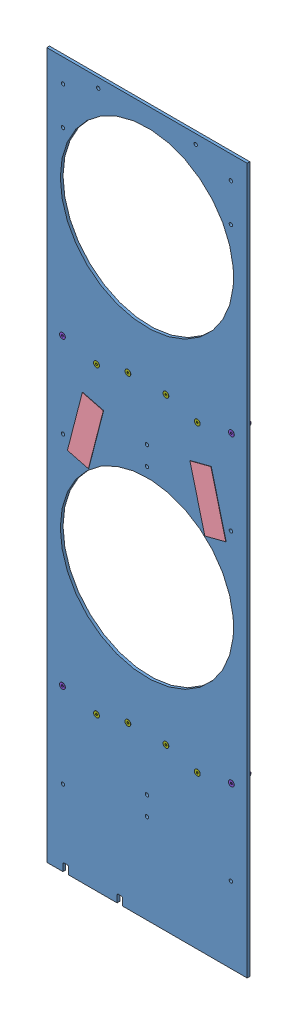
SolidWorks assembly GE-19128, configuration Default. Lengths in mm.
Overall size (469.9 1654.81 45.24).
39 component instances, 8 part files, 83 mates.
Components (placement in the parent):
- GE-19124-1: GE-19124 [Default] at origin size (469.9 1654.81 6.35)
- GE-19029-1: GE-19029 [Default] at (-12.7 406.807 0) x (0 0 -1) z (-0.965926 -0.258819 0) size (38.1 38.1 152.4)
- GE-19029-2: GE-19029 [Default] at (-12.7 1118.007 0) x (0 0 -1) z (-0.965926 -0.258819 0) size (38.1 38.1 152.4)
- GE-19029-3: GE-19029 [Default] at (159.9071 367.363 0) x (0 0 -1) z (-0.965926 0.258819 0) size (38.1 38.1 152.4)
- GE-19029-4: GE-19029 [Default] at (159.9071 1078.563 0) x (0 0 -1) z (-0.965926 0.258819 0) size (38.1 38.1 152.4)
- spacer_.257_1_.5-1: spacer_.257_1_.5 [Default] at (198.12 1088.0459 -25.4) x (-0.923728 -0.383049 0) z (-0.383049 0.923728 0) size (12.7 25.4 12.7)
- spacer_.257_1_.5-2: spacer_.257_1_.5 [Default] at (-198.12 1088.0459 -25.4) x (-0.923728 -0.383049 0) z (-0.383049 0.923728 0) size (12.7 25.4 12.7)
- spacer_.257_1_.5-3: spacer_.257_1_.5 [Default] at (-198.12 376.8459 -25.4) x (-0.923728 -0.383049 0) z (-0.383049 0.923728 0) size (12.7 25.4 12.7)
- spacer_.257_1_.5-4: spacer_.257_1_.5 [Default] at (198.12 376.8459 -25.4) x (-0.923728 -0.383049 0) z (-0.383049 0.923728 0) size (12.7 25.4 12.7)
- VisionTape-1: VisionTape [Default] at (185.7119 861.6861 7.1437) x (-0.968246 -0.25 0) z (0 0 -1) size (50.8 139.7 0.79)
- VisionTape-2: VisionTape [Default] at (-136.525 848.9861 7.1437) x (-0.968246 0.25 0) z (0 0 -1) size (50.8 139.7 0.79)
- nylock_.25_20-1: nylock_.25_20 [Default] at (-198.12 376.8459 -25.4) x (1 0 0) z (0 1 0) size (11.11 7.94 12.83)
- nylock_.25_20-2: nylock_.25_20 [Default] at (-118.1748 358.8231 -3.175) x (0.987351 0.158553 0) z (-0.158553 0.987351 0) size (11.11 7.94 12.83)
- nylock_.25_20-4: nylock_.25_20 [Default] at (-44.5713 378.5452 -3.175) x (0.959125 0.282984 0) z (-0.282984 0.959125 0) size (11.11 7.94 12.83)
- nylock_.25_20-6: nylock_.25_20 [Default] at (44.5713 378.5452 -3.175) x (0.928571 0.371154 0) z (-0.371154 0.928571 0) size (11.11 7.94 12.83)
- nylock_.25_20-8: nylock_.25_20 [Default] at (118.1748 358.8231 -3.175) x (0.906989 0.421154 0) z (-0.421154 0.906989 0) size (11.11 7.94 12.83)
- nylock_.25_20-10: nylock_.25_20 [Default] at (198.12 376.8459 -25.4) x (0.902849 0.429957 0) z (-0.429957 0.902849 0) size (11.11 7.94 12.83)
- nylock_.25_20-12: nylock_.25_20 [Default] at (-198.12 1088.0459 -25.4) x (0.919615 0.39282 0) z (-0.39282 0.919615 0) size (11.11 7.94 12.83)
- nylock_.25_20-14: nylock_.25_20 [Default] at (-118.1748 1070.0231 -3.175) x (0.952324 0.305088 0) z (-0.305088 0.952324 0) size (11.11 7.94 12.83)
- nylock_.25_20-16: nylock_.25_20 [Default] at (-44.5713 1089.7452 -3.175) x (0.985697 0.168526 0) z (-0.168526 0.985697 0) size (11.11 7.94 12.83)
- nylock_.25_20-18: nylock_.25_20 [Default] at (44.5713 1089.7452 -3.175) x (1 0 0) z (0 1 0) size (11.11 7.94 12.83)
- nylock_.25_20-20: nylock_.25_20 [Default] at (118.1748 1070.0231 -3.175) x (0.985697 -0.168526 0) z (0.168526 0.985697 0) size (11.11 7.94 12.83)
- nylock_.25_20-22: nylock_.25_20 [Default] at (198.12 1088.0459 -25.4) x (0.952324 -0.305088 0) z (0.305088 0.952324 0) size (11.11 7.94 12.83)
- Hook_1_6-1: Hook_1_6 [Default] at (12.7 1118.007 -6.35) x (0.965926 -0.258819 0) z (0 0 1) size (152.4 1.59 25.4)
- Hook_1_6-2: Hook_1_6 [Default] at (-159.9071 1078.563 -6.35) x (0.965926 0.258819 0) z (0 0 1) size (152.4 1.59 25.4)
- Hook_1_6-3: Hook_1_6 [Default] at (12.7 406.807 -6.35) x (0.965926 -0.258819 0) z (0 0 1) size (152.4 1.59 25.4)
- Hook_1_6-4: Hook_1_6 [Default] at (-159.9071 367.363 -6.35) x (0.965926 0.258819 0) z (0 0 1) size (152.4 1.59 25.4)
- flat_hex_.25_20_1-1: flat_hex_.25_20_1 [91253A542] at (-118.1748 1070.0231 6.5545) size (13.49 13.49 25.61)
- flat_hex_.25_20_1-9: flat_hex_.25_20_1 [91253A542] at (-44.5713 1089.7452 6.5545) x (0.987351 0.158553 0) z (0 0 1) size (13.49 13.49 25.61)
- flat_hex_.25_20_1-11: flat_hex_.25_20_1 [91253A542] at (44.5713 1089.7452 6.5545) x (0.959125 0.282984 0) z (0 0 1) size (13.49 13.49 25.61)
- flat_hex_.25_20_1-13: flat_hex_.25_20_1 [91253A542] at (118.1748 1070.0231 6.5545) x (0.928571 0.371154 0) z (0 0 1) size (13.49 13.49 25.61)
- flat_hex_.25_20_1-15: flat_hex_.25_20_1 [91253A542] at (-118.1748 358.8231 6.5545) x (0.906989 0.421154 0) z (0 0 1) size (13.49 13.49 25.61)
- flat_hex_.25_20_1-17: flat_hex_.25_20_1 [91253A542] at (-44.5713 378.5452 6.5545) x (0.902849 0.429957 0) z (0 0 1) size (13.49 13.49 25.61)
- flat_hex_.25_20_1-19: flat_hex_.25_20_1 [91253A542] at (44.5713 378.5452 6.5545) x (0.919615 0.39282 0) z (0 0 1) size (13.49 13.49 25.61)
- flat_hex_.25_20_1-21: flat_hex_.25_20_1 [91253A542] at (118.1748 358.8231 6.5545) x (0.952324 0.305088 0) z (0 0 1) size (13.49 13.49 25.61)
- flat_hex_.25_20_1.75-1: flat_hex_.25_20_1.75 [91253A548] at (-198.12 376.8459 6.5545) size (13.49 13.49 44.66)
- flat_hex_.25_20_1.75-2: flat_hex_.25_20_1.75 [91253A548] at (198.12 376.8459 6.5545) x (0.987351 0.158553 0) z (0 0 1) size (13.49 13.49 44.66)
- flat_hex_.25_20_1.75-4: flat_hex_.25_20_1.75 [91253A548] at (-198.12 1088.0459 6.5545) x (0.959125 0.282984 0) z (0 0 1) size (13.49 13.49 44.66)
- flat_hex_.25_20_1.75-6: flat_hex_.25_20_1.75 [91253A548] at (198.12 1088.0459 6.5545) x (0.928571 0.371154 0) z (0 0 1) size (13.49 13.49 44.66)
Mates (geometry in assembly coordinates):
- Coincident1: coincident: circle of GE-19124-1; unknown of GE-19029-1
- Coincident9: coincident: plane of GE-19124-1 through (0 0 0) normal (0 0 -1); plane of spacer_.257_1_.5-4 through (198.12 376.8459 0) normal (0 0 1)
- Coincident10: coincident: plane of GE-19124-1 through (0 0 0) normal (0 0 -1); plane of spacer_.257_1_.5-3 through (-198.12 376.8459 0) normal (0 0 1)
- Coincident11: coincident: plane of GE-19124-1 through (0 0 0) normal (0 0 -1); plane of spacer_.257_1_.5-2 through (-198.12 1088.0459 0) normal (0 0 1)
- Coincident12: coincident: plane of GE-19124-1 through (0 0 0) normal (0 0 -1); plane of spacer_.257_1_.5-1 through (198.12 1088.0459 0) normal (0 0 1)
- Concentric5: concentric: cylinder of GE-19124-1 through (-118.1748 358.8231 6.35) axis (0 0 1) radius 3.3782; cylinder of GE-19029-1 through (-118.1748 358.8231 0) axis (0 0 1) radius 3.3782
- Coincident13: coincident: circle of GE-19124-1; circle of GE-19029-3
- Concentric6: concentric: cylinder of GE-19124-1 through (118.1748 358.8231 6.35) axis (0 0 1) radius 3.3782; cylinder of GE-19029-3 through (118.1748 358.8231 0) axis (0 0 1) radius 3.3782
- Coincident14: coincident: circle of GE-19124-1; circle of GE-19029-4
- Concentric7: concentric: cylinder of GE-19124-1 through (118.1748 1070.0231 6.35) axis (0 0 1) radius 3.3782; cylinder of GE-19029-4 through (118.1748 1070.0231 0) axis (0 0 1) radius 3.3782
- Coincident15: coincident: circle of GE-19124-1; circle of GE-19029-2
- Concentric8: concentric: cylinder of GE-19124-1 through (-118.1748 1070.0231 6.35) axis (0 0 1) radius 3.3782; cylinder of GE-19029-2 through (-118.1748 1070.0231 0) axis (0 0 1) radius 3.3782
- Concentric9: concentric: circle of GE-19124-1; circle of spacer_.257_1_.5-1
- Concentric10: concentric: circle of GE-19124-1; circle of spacer_.257_1_.5-2
- Concentric11: concentric: circle of GE-19124-1; circle of spacer_.257_1_.5-4
- Concentric12: concentric: circle of GE-19124-1; circle of spacer_.257_1_.5-3
- Coincident16: coincident: plane of GE-19124-1 through (0 0 6.35) normal (0 0 1); plane of ? through (-132.5429 873.8959 6.35) normal (0 0 -1)
- Coincident17: coincident: plane of GE-19124-1 through (0 0 6.35) normal (0 0 1); plane of ? through (188.1614 861.6861 6.35) normal (0 0 -1)
- Distance1: distance = 203.2 mm: point of assembly; point of assembly; point of VisionTape-2; point of VisionTape-1
- Symmetric2: symmetric: plane of ? through (138.9745 848.9861 6.35) normal (-0.968246 -0.25 0); plane of ? through (-132.5429 873.8959 6.35) normal (0.968246 -0.25 0)
- Coincident42: coincident: plane of assembly; plane of assembly; plane of spacer_.257_1_.5-3 through (-198.12 376.8459 -25.4) normal (0 0 -1); plane of nylock_.25_20-1 through (-198.12 376.8459 -25.4) normal (0 0 1)
- Coincident43: coincident: plane of assembly; plane of assembly; plane of GE-19029-1 through (-150.0461 330.5612 -3.175) normal (0 0 -1); plane of nylock_.25_20-2 through (-118.1748 358.8231 -3.175) normal (0 0 1)
- Coincident44: coincident: plane of assembly; plane of assembly; plane of GE-19029-1 through (-150.0461 330.5612 -3.175) normal (0 0 -1); plane of nylock_.25_20-4 through (-44.5713 378.5452 -3.175) normal (0 0 1)
- Coincident45: coincident: plane of assembly; plane of assembly; plane of GE-19029-3 through (2.839 370.0053 -3.175) normal (0 0 -1); plane of nylock_.25_20-6 through (44.5713 378.5452 -3.175) normal (0 0 1)
- Coincident46: coincident: plane of assembly; plane of assembly; plane of GE-19029-3 through (2.839 370.0053 -3.175) normal (0 0 -1); plane of nylock_.25_20-8 through (118.1748 358.8231 -3.175) normal (0 0 1)
- Coincident47: coincident: plane of assembly; plane of assembly; plane of spacer_.257_1_.5-4 through (198.12 376.8459 -25.4) normal (0 0 -1); plane of nylock_.25_20-10 through (198.12 376.8459 -25.4) normal (0 0 1)
- Coincident48: coincident: plane of assembly; plane of assembly; plane of spacer_.257_1_.5-2 through (-198.12 1088.0459 -25.4) normal (0 0 -1); plane of nylock_.25_20-12 through (-198.12 1088.0459 -25.4) normal (0 0 1)
- Coincident49: coincident: plane of assembly; plane of assembly; plane of GE-19029-2 through (-150.0461 1041.7612 -3.175) normal (0 0 -1); plane of nylock_.25_20-14 through (-118.1748 1070.0231 -3.175) normal (0 0 1)
- Coincident50: coincident: plane of assembly; plane of assembly; plane of GE-19029-2 through (-150.0461 1041.7612 -3.175) normal (0 0 -1); plane of nylock_.25_20-16 through (-44.5713 1089.7452 -3.175) normal (0 0 1)
- Coincident51: coincident: plane of assembly; plane of assembly; plane of GE-19029-4 through (2.839 1081.2053 -3.175) normal (0 0 -1); plane of nylock_.25_20-18 through (44.5713 1089.7452 -3.175) normal (0 0 1)
- Coincident52: coincident: plane of assembly; plane of assembly; plane of GE-19029-4 through (2.839 1081.2053 -3.175) normal (0 0 -1); plane of nylock_.25_20-20 through (118.1748 1070.0231 -3.175) normal (0 0 1)
- Coincident53: coincident: plane of assembly; plane of assembly; plane of spacer_.257_1_.5-1 through (198.12 1088.0459 -25.4) normal (0 0 -1); plane of nylock_.25_20-22 through (198.12 1088.0459 -25.4) normal (0 0 1)
- Coincident54: coincident: plane of assembly; plane of assembly; plane of GE-19029-4 through (12.7 1118.007 -38.1) normal (0.258819 0.965926 0); plane of Hook_1_6-1 through (12.7 1118.007 -6.35) normal (-0.258819 -0.965926 0)
- Coincident55: coincident: plane of assembly; plane of assembly; plane of GE-19029-2 through (-159.9071 1078.563 -38.1) normal (-0.258819 0.965926 0); plane of Hook_1_6-2 through (-159.9071 1078.563 -6.35) normal (0.258819 -0.965926 0)
- Coincident56: coincident: plane of assembly; plane of assembly; plane of GE-19029-1 through (-159.9071 367.363 -38.1) normal (-0.258819 0.965926 0); plane of Hook_1_6-4 through (-159.9071 367.363 -6.35) normal (0.258819 -0.965926 0)
- Coincident57: coincident: plane of assembly; plane of assembly; plane of GE-19029-3 through (12.7 406.807 -38.1) normal (0.258819 0.965926 0); plane of Hook_1_6-3 through (12.7 406.807 -6.35) normal (-0.258819 -0.965926 0)
- Coincident58: coincident: plane of assembly; plane of assembly; plane of GE-19029-4 through (159.9071 1078.563 0) normal (0.965926 -0.258819 0); plane of Hook_1_6-1 through (160.318 1080.0964 -6.35) normal (0.965926 -0.258819 0)
- Coincident59: coincident: plane of assembly; plane of assembly; plane of GE-19029-3 through (159.9071 367.363 0) normal (0.965926 -0.258819 0); plane of Hook_1_6-3 through (160.318 368.8964 -6.35) normal (0.965926 -0.258819 0)
- Coincident60: coincident: plane of assembly; plane of assembly; plane of GE-19029-1 through (-12.7 406.807 0) normal (0.965926 0.258819 0); plane of Hook_1_6-4 through (-13.1109 408.3405 -6.35) normal (0.965926 0.258819 0)
- Coincident61: coincident: plane of assembly; plane of assembly; plane of GE-19029-2 through (-12.7 1118.007 0) normal (0.965926 0.258819 0); plane of Hook_1_6-2 through (-13.1109 1119.5405 -6.35) normal (0.965926 0.258819 0)
- Width1: width: plane of assembly; plane of assembly; plane of assembly; plane of assembly; plane of Hook_1_6-1 through (13.1109 1119.5405 -31.75) normal (0 0 -1); plane of Hook_1_6-1 through (13.1109 1119.5405 -6.35) normal (0 0 1); plane of GE-19029-4 through (11.8782 1114.9402 -38.1) normal (0 0 -1); plane of GE-19029-4 through (12.7 1118.007 0) normal (0 0 1)
- Width2: width: plane of assembly; plane of assembly; plane of assembly; plane of assembly; plane of Hook_1_6-2 through (-160.318 1080.0964 -6.35) normal (0 0 1); plane of Hook_1_6-2 through (-160.318 1080.0964 -31.75) normal (0 0 -1); plane of GE-19029-2 through (-159.9071 1078.563 0) normal (0 0 1); plane of GE-19029-2 through (-159.0853 1075.4962 -38.1) normal (0 0 -1)
- Width3: width: plane of assembly; plane of assembly; plane of assembly; plane of assembly; plane of Hook_1_6-3 through (13.1109 408.3405 -31.75) normal (0 0 -1); plane of Hook_1_6-3 through (13.1109 408.3405 -6.35) normal (0 0 1); plane of GE-19029-3 through (11.8782 403.7402 -38.1) normal (0 0 -1); plane of GE-19029-3 through (12.7 406.807 0) normal (0 0 1)
- Width4: width: plane of assembly; plane of assembly; plane of assembly; plane of assembly; plane of Hook_1_6-4 through (-160.318 368.8964 -6.35) normal (0 0 1); plane of Hook_1_6-4 through (-160.318 368.8964 -31.75) normal (0 0 -1); plane of GE-19029-1 through (-159.9071 367.363 0) normal (0 0 1); plane of GE-19029-1 through (-159.0853 364.2962 -38.1) normal (0 0 -1)
- Concentric46: concentric: circle of GE-19124-1; circle of flat_hex_.25_20_1-1
- Coincident63: coincident: cone of GE-19124-1 through (-118.1748 1070.0231 6.35) axis (0 0 -1); cylinder of flat_hex_.25_20_1-1 through (-118.1748 1070.0231 2.4651) axis (0 0 -1) radius 715.585
- Concentric47: concentric: cylinder of assembly; cylinder of assembly; cylinder of nylock_.25_20-14 through (-118.1748 1070.0231 -3.175) axis (0 0 -1) radius 3.175; cylinder of flat_hex_.25_20_1-1 through (-118.1748 1070.0231 -18.8455) axis (0 0 -1) radius 3.175
- Concentric48: concentric: unknown of GE-19124-1; unknown of flat_hex_.25_20_1-9
- Coincident64: coincident: cylinder of GE-19124-1 through (-44.5713 1089.7452 6.35) axis (0 0 -1) radius 715.585; cylinder of flat_hex_.25_20_1-9 through (-44.5713 1089.7452 2.4651) axis (0 0 -1) radius 715.585
- Concentric49: concentric: cylinder of assembly; cylinder of assembly; cylinder of nylock_.25_20-16 through (-44.5713 1089.7452 -3.175) axis (0 0 -1) radius 3.175; cylinder of flat_hex_.25_20_1-9 through (-44.5713 1089.7452 -18.8455) axis (0 0 -1) radius 3.175
- Concentric50: concentric: unknown of GE-19124-1; unknown of flat_hex_.25_20_1-11
- Coincident65: coincident: cylinder of GE-19124-1 through (44.5713 1089.7452 6.35) axis (0 0 -1) radius 715.585; cylinder of flat_hex_.25_20_1-11 through (44.5713 1089.7452 2.4651) axis (0 0 -1) radius 715.585
- Concentric51: concentric: cylinder of assembly; cylinder of assembly; cylinder of nylock_.25_20-18 through (44.5713 1089.7452 -3.175) axis (0 0 -1) radius 3.175; cylinder of flat_hex_.25_20_1-11 through (44.5713 1089.7452 -18.8455) axis (0 0 -1) radius 3.175
- Concentric52: concentric: unknown of GE-19124-1; unknown of flat_hex_.25_20_1-13
- Coincident66: coincident: cylinder of GE-19124-1 through (118.1748 1070.0231 6.35) axis (0 0 -1) radius 715.585; cylinder of flat_hex_.25_20_1-13 through (118.1748 1070.0231 2.4651) axis (0 0 -1) radius 715.585
- Concentric53: concentric: cylinder of assembly; cylinder of assembly; cylinder of nylock_.25_20-20 through (118.1748 1070.0231 -3.175) axis (0 0 -1) radius 3.175; cylinder of flat_hex_.25_20_1-13 through (118.1748 1070.0231 -18.8455) axis (0 0 -1) radius 3.175
- Concentric54: concentric: unknown of GE-19124-1; unknown of flat_hex_.25_20_1-15
- Coincident67: coincident: cylinder of GE-19124-1 through (-118.1748 358.8231 6.35) axis (0 0 -1) radius 715.585; cylinder of flat_hex_.25_20_1-15 through (-118.1748 358.8231 2.4651) axis (0 0 -1) radius 715.585
- Concentric55: concentric: cylinder of assembly; cylinder of assembly; cylinder of nylock_.25_20-2 through (-118.1748 358.8231 -3.175) axis (0 0 -1) radius 3.175; cylinder of flat_hex_.25_20_1-15 through (-118.1748 358.8231 -18.8455) axis (0 0 -1) radius 3.175
- Concentric56: concentric: unknown of GE-19124-1; unknown of flat_hex_.25_20_1-17
- Coincident68: coincident: cylinder of GE-19124-1 through (-44.5713 378.5452 6.35) axis (0 0 -1) radius 715.585; cylinder of flat_hex_.25_20_1-17 through (-44.5713 378.5452 2.4651) axis (0 0 -1) radius 715.585
- Concentric57: concentric: cylinder of assembly; cylinder of assembly; cylinder of nylock_.25_20-4 through (-44.5713 378.5452 -3.175) axis (0 0 -1) radius 3.175; cylinder of flat_hex_.25_20_1-17 through (-44.5713 378.5452 -18.8455) axis (0 0 -1) radius 3.175
- Concentric58: concentric: unknown of GE-19124-1; unknown of flat_hex_.25_20_1-19
- Coincident69: coincident: cylinder of GE-19124-1 through (44.5713 378.5452 6.35) axis (0 0 -1) radius 715.585; cylinder of flat_hex_.25_20_1-19 through (44.5713 378.5452 2.4651) axis (0 0 -1) radius 715.585
- Concentric59: concentric: cylinder of assembly; cylinder of assembly; cylinder of nylock_.25_20-6 through (44.5713 378.5452 -3.175) axis (0 0 -1) radius 3.175; cylinder of flat_hex_.25_20_1-19 through (44.5713 378.5452 -18.8455) axis (0 0 -1) radius 3.175
- Concentric60: concentric: unknown of GE-19124-1; unknown of flat_hex_.25_20_1-21
- Coincident70: coincident: cylinder of GE-19124-1 through (118.1748 358.8231 6.35) axis (0 0 -1) radius 715.585; cylinder of flat_hex_.25_20_1-21 through (118.1748 358.8231 2.4651) axis (0 0 -1) radius 715.585
- Concentric61: concentric: cylinder of assembly; cylinder of assembly; cylinder of nylock_.25_20-8 through (118.1748 358.8231 -3.175) axis (0 0 -1) radius 3.175; cylinder of flat_hex_.25_20_1-21 through (118.1748 358.8231 -18.8455) axis (0 0 -1) radius 3.175
- Concentric62: concentric: circle of GE-19124-1; circle of flat_hex_.25_20_1.75-1
- Coincident72: coincident: cylinder of GE-19124-1 through (-198.12 376.8459 6.35) axis (0 0 -1) radius 715.585; cylinder of flat_hex_.25_20_1.75-1 through (-198.12 376.8459 2.4651) axis (0 0 -1) radius 715.585
- Concentric63: concentric: cylinder of assembly; cylinder of assembly; cylinder of nylock_.25_20-1 through (-198.12 376.8459 -25.4) axis (0 0 -1) radius 3.175; cylinder of flat_hex_.25_20_1.75-1 through (-198.12 376.8459 -37.8955) axis (0 0 -1) radius 3.175
- Concentric64: concentric: unknown of GE-19124-1; unknown of flat_hex_.25_20_1.75-2
- Coincident73: coincident: cylinder of GE-19124-1 through (198.12 376.8459 6.35) axis (0 0 -1) radius 715.585; cylinder of flat_hex_.25_20_1.75-2 through (198.12 376.8459 2.4651) axis (0 0 -1) radius 715.585
- Concentric65: concentric: cylinder of assembly; cylinder of assembly; cylinder of nylock_.25_20-10 through (198.12 376.8459 -25.4) axis (0 0 -1) radius 3.175; cylinder of flat_hex_.25_20_1.75-2 through (198.12 376.8459 -37.8955) axis (0 0 -1) radius 3.175
- Concentric66: concentric: unknown of GE-19124-1; unknown of flat_hex_.25_20_1.75-4
- Coincident74: coincident: cylinder of GE-19124-1 through (-198.12 1088.0459 6.35) axis (0 0 -1) radius 715.585; cylinder of flat_hex_.25_20_1.75-4 through (-198.12 1088.0459 2.4651) axis (0 0 -1) radius 715.585
- Concentric67: concentric: cylinder of assembly; cylinder of assembly; cylinder of nylock_.25_20-12 through (-198.12 1088.0459 -25.4) axis (0 0 -1) radius 3.175; cylinder of flat_hex_.25_20_1.75-4 through (-198.12 1088.0459 -37.8955) axis (0 0 -1) radius 3.175
- Concentric68: concentric: unknown of GE-19124-1; unknown of flat_hex_.25_20_1.75-6
- Coincident75: coincident: cylinder of GE-19124-1 through (198.12 1088.0459 6.35) axis (0 0 -1) radius 715.585; cylinder of flat_hex_.25_20_1.75-6 through (198.12 1088.0459 2.4651) axis (0 0 -1) radius 715.585
- Concentric69: concentric: cylinder of assembly; cylinder of assembly; cylinder of nylock_.25_20-22 through (198.12 1088.0459 -25.4) axis (0 0 -1) radius 3.175; cylinder of flat_hex_.25_20_1.75-6 through (198.12 1088.0459 -37.8955) axis (0 0 -1) radius 3.175
- Distance2: distance = 996.95 mm: line of GE-19124-1; line of VisionTape-1 through (150.7869 996.95 6.35) axis (0 0 1)
- Distance3: distance = 984.25 mm: plane of GE-19124-1 through (-234.95 0 6.35) normal (0 -1 0); line of VisionTape-1 through (101.6 984.25 6.35) axis (0 0 1)
- Distance4: distance = 996.95 mm: line of VisionTape-2 through (-150.7869 996.95 6.35) axis (0 0 1); plane of GE-19124-1 through (-234.95 0 6.35) normal (0 -1 0)
